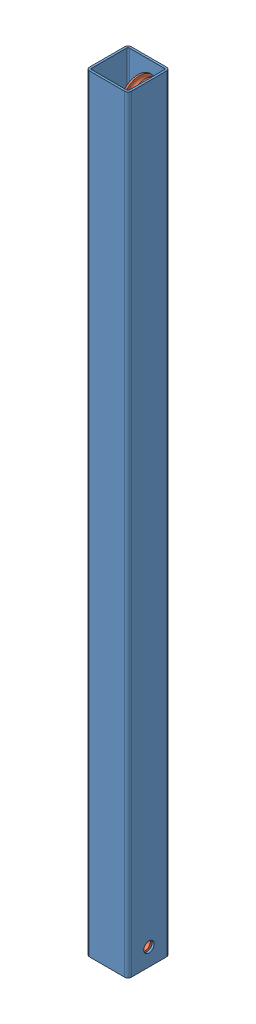
SolidWorks assembly Колено2СБ, configuration По умолчанию. Lengths in mm.
Overall size (60 1100 60).
3 component instances, 2 part files, 5 mates.
Components (placement in the parent):
- ТрубПр60_60-1: ТрубПр60_60 [По умолчанию] at origin size (60 1100 60)
- Ролик1-1: Ролик1 [По умолчанию] at (20.5409 25 0) x (0 -1 0) z (0 0 1) size (50 12.92 50)
- Ролик1-2: Ролик1 [По умолчанию] at (20.5409 1075 0) x (0 -1 0) z (0 0 1) size (50 12.92 50)
Mates (geometry in assembly coordinates):
- Совпадение1: coincident anti-aligned: plane of ТрубПр60_60-1 through (27 1100 -25) normal (-1 0 0); plane of Ролик1-1 through (27 7.739 0) normal (1 0 0)
- Концентричный1: concentric aligned: cylinder of ТрубПр60_60-1 through (-30 25 0) axis (1 0 0) radius 7.5; cylinder of Ролик1-1 through (61.4733 25 0) axis (1 0 0) radius 7.5
- Совпадение2: coincident: plane of ТрубПр60_60-1 through (27 1100 -25) normal (-1 0 0); plane of Ролик1-2 through (27 1057.739 -2) normal (1 0 0)
- Расстояние3: distance = 25 mm: cylinder of Ролик1-2 through (61.4733 1075 0) axis (1 0 0) radius 7.5; plane of ТрубПр60_60-1 through (-25 1100 25) normal (0 1 0)
- Расстояние4: distance = 27 mm: cylinder of Ролик1-2 through (61.4733 1075 0) axis (1 0 0) radius 7.5; plane of ТрубПр60_60-1 through (-25 1100 -27) normal (0 0 1)
